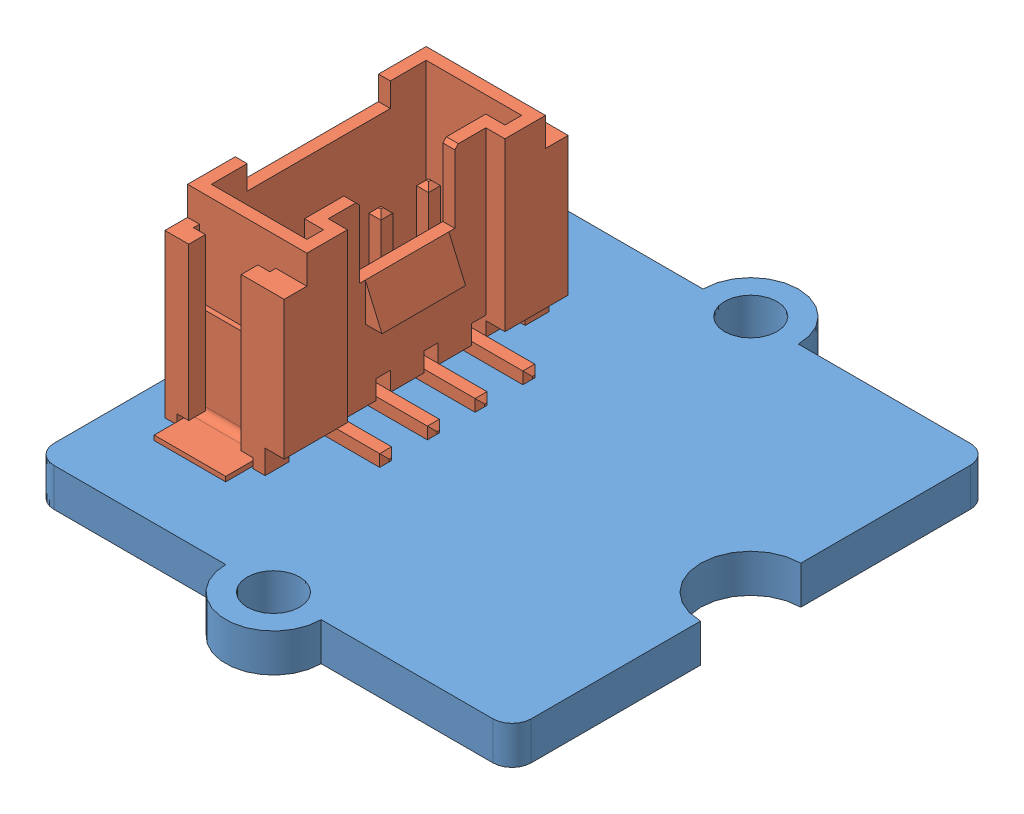
SolidWorks assembly PCB Grove 20x20 SMD Vertical, configuration Défaut. Lengths in mm.
Overall size (20 9.6 24).
2 component instances, 2 part files, 3 mates.
Components (placement in the parent):
- PCB grove 20x20-1: PCB grove 20x20 [Défaut] at (-3.5095 1.8163 24) size (20 1.6 24)
- Connector Grove SMD Vertical-1: Connector Grove SMD Vertical [Défaut] at (-7.1095 2.6163 24) x (0 0 -1) z (1 0 0) size (14 8 6.5)
Mates (geometry in assembly coordinates):
- Coïncidente1: coincident anti-aligned: plane of PCB Grove 20x20-1 through (-3.5095 1.8163 24) normal (0 0 1); plane of Connector Grove SMD Vertical-1 through (-7.1095 2.6163 24) normal (0 0 -1)
- Distance1: distance = 1.4 mm aligned: plane of PCB Grove 20x20-1 through (-13.5095 2.6163 24) normal (-1 0 0); plane of Connector Grove SMD Vertical-1 through (-12.1095 10.6163 29) normal (-1 0 0)
- Coïncidente3: coincident anti-aligned: plane of PCB Grove 20x20-1 through (-3.5095 2.6163 24) normal (0 1 0); plane of Connector Grove SMD Vertical-1 through (-11.5095 2.6163 29.5) normal (0 -1 0)
